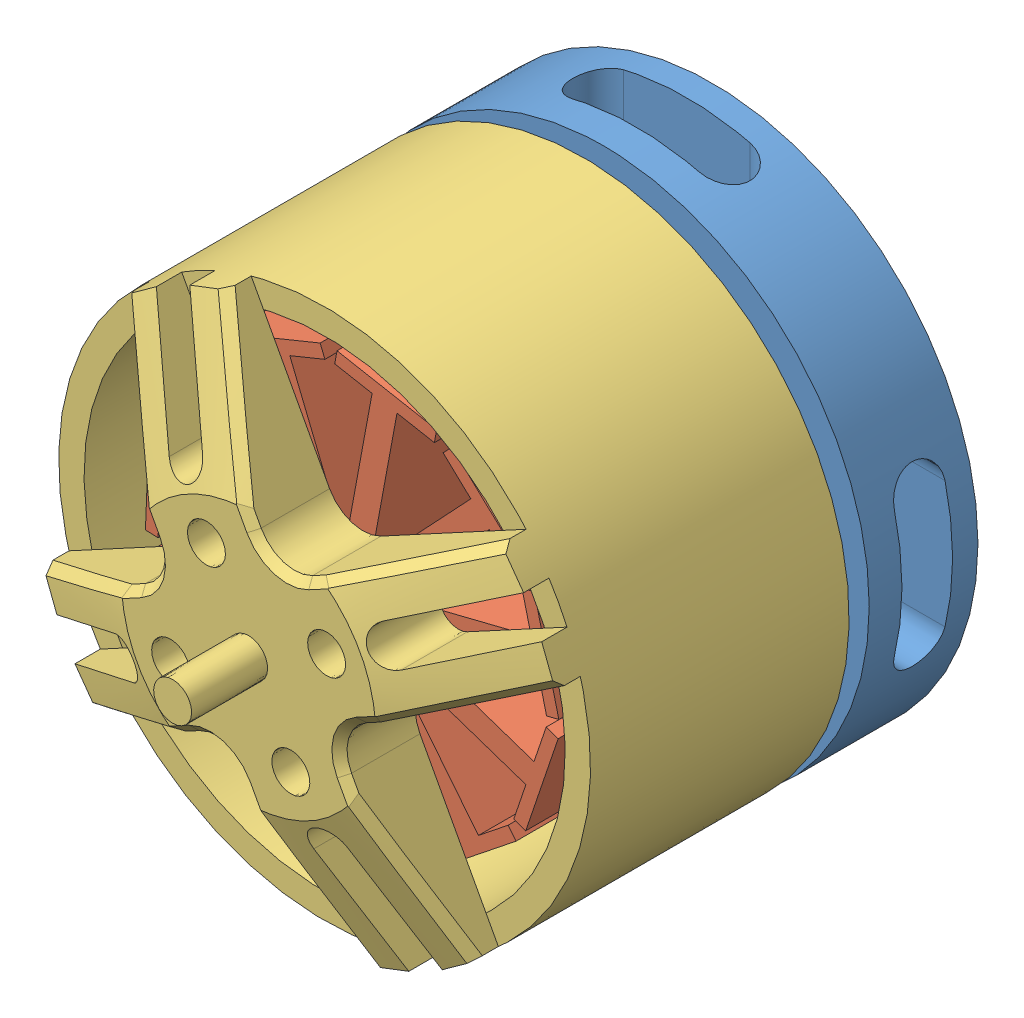
SolidWorks assembly motor, configuration Varsayılan. Lengths in mm.
Overall size (28.46 28.46 36).
3 component instances, 3 part files, 4 mates.
Components (placement in the parent):
- motor-taban-1: motor-taban [Varsayılan] at (-1.063 0.0213 13.3538) size (21 21 15.29)
- motor-strator-1: motor-strator [Varsayılan] at (-1.063 0.0213 14.1462) x (-0.892183 0.451675 0) z (0 0 1) size (16.41 16.24 8.71)
- motor-can-1: motor-can [Varsayılan] at (-1.063 0.0213 13.6462) x (-0.47572 0.879597 0) z (0 0 1) size (21 21 36)
Mates (geometry in assembly coordinates):
- Eş Merkezli1: concentric aligned: cylinder of motor-taban-1 through (-1.063 0.0213 17.6462) axis (0 0 1) radius 1.5; cylinder of motor-strator-1 through (-1.063 0.0213 17.6462) axis (0 0 1) radius 1.5
- Uzaklık1: distance = 1 mm aligned: plane of motor-strator-1 through (-1.063 0.0213 27.6462) normal (0 0 1); plane of motor-taban-1 through (-1.063 0.0213 28.6462) normal (0 0 1)
- Eş Merkezli2: concentric aligned: cylinder of motor-taban-1 through (-1.063 0.0213 12.6462) axis (0 0 1) radius 0.75; cylinder of motor-can-1 through (-1.063 0.0213 -1.3538) axis (0 0 1) radius 0.75
- Çakışık2: coincident anti-aligned: plane of motor-taban-1 through (-1.063 0.0213 28.6462) normal (0 0 1); plane of motor-can-1 through (-1.063 0.0213 28.6462) normal (0 0 -1)
